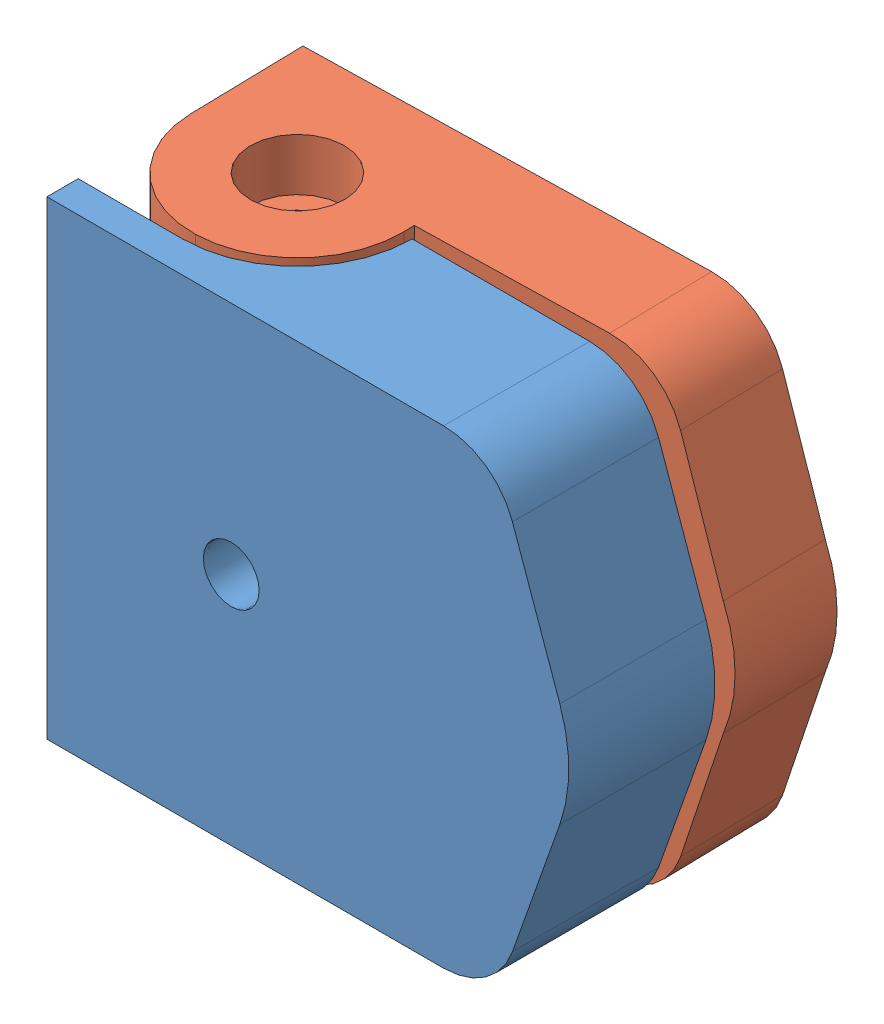
SolidWorks assembly Assem1, configuration Default. Lengths in mm.
Overall size (50.52 45 25.9).
2 component instances, 2 part files, 2 mates.
Components (placement in the parent):
- P-GL-002_REV_0-1: P-GL-002_REV_0 [Default] at (-221.4086 -58.9376 18.0869) size (50 45 24)
- P-GL-001_REV_0-1: P-GL-001_REV_0 [Default] at (-60.1511 13.7274 17.7855) x (0.999748 0 -0.022433) z (-0.022433 0 -0.999748) size (50.06 45 21)
Mates (geometry in assembly coordinates):
- Concentric1: concentric aligned: cylinder of P-GL-002_REV_0-1 through (-73.5811 -6.5656 18.0869) axis (0 1 0) radius 3.5; cylinder of P-GL-001_REV_0-1 through (-73.5811 -6.5657 18.0869) axis (0 1 0) radius 2.675
- Width1: width: plane of P-GL-001_REV_0-1 through (-59.3296 38.4344 7.7646) normal (0 1 0); plane of P-GL-001_REV_0-1 through (-59.3296 -6.5656 7.7646) normal (0 -1 0); plane of P-GL-002_REV_0-1 through (-58.7224 -6.5656 28.0869) normal (0 -1 0); plane of P-GL-002_REV_0-1 through (-58.7224 38.4344 28.0869) normal (0 1 0)
